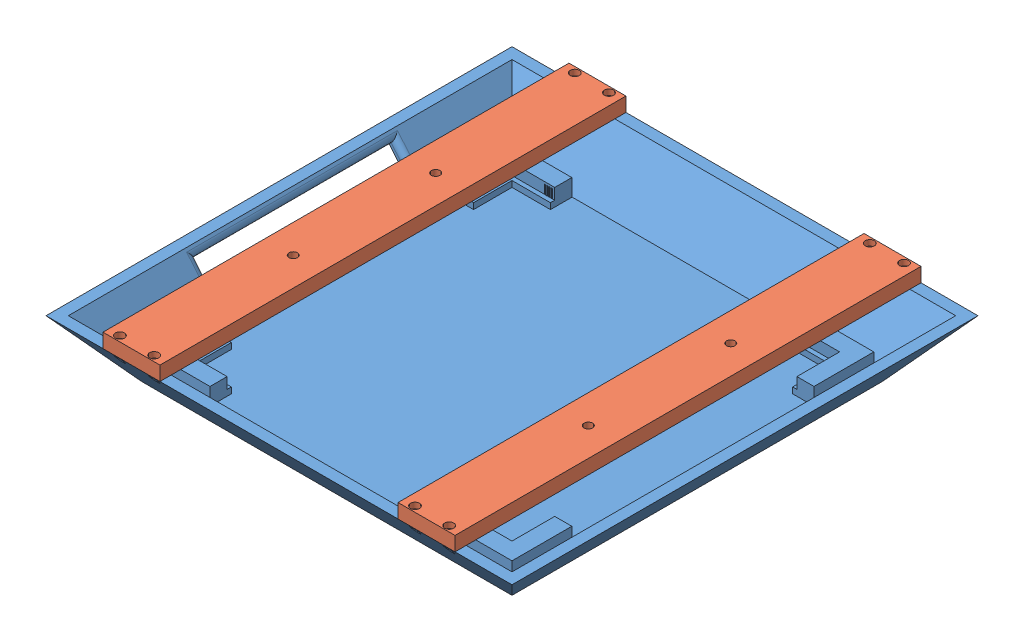
SolidWorks assembly radome_assembly(without_SoC), configuration Default. Lengths in mm.
Overall size (163.56 25 163.57).
3 component instances, 2 part files, 5 mates.
Components (placement in the parent):
- aircraft_BLE_radome-1: aircraft_BLE_radome [Default] at origin size (163.56 20 163.56)
- radome_crossbar-1: radome_crossbar [Default] at (-51.782 20 0.0005) x (0 0 -1) z (1 0 0) size (163.57 5 20)
- radome_crossbar-2: radome_crossbar [Default] at (51.782 20 0.003) x (0 0 -1) z (1 0 0) size (163.57 5 20)
Mates (geometry in assembly coordinates):
- Coincident1: coordinate: point of aircraft_BLE_radome-1
- Coincident2: coincident aligned: circle of aircraft_BLE_radome-1; circle of radome_crossbar-1
- Concentric1: concentric anti-aligned: cylinder of aircraft_BLE_radome-1 through (-57.782 -1.65 79.8255) axis (0 1 0) radius 1; cylinder of radome_crossbar-1 through (-57.782 25 79.8255) axis (0 -1 0) radius 1
- Coincident3: coincident: circle of aircraft_BLE_radome-1; circle of radome_crossbar-2
- Parallel1: parallel aligned: line of aircraft_BLE_radome-1 through (-81.782 20 81.782) axis (1 0 0); line of radome_crossbar-2 through (41.782 25 81.788) axis (1 0 0)
